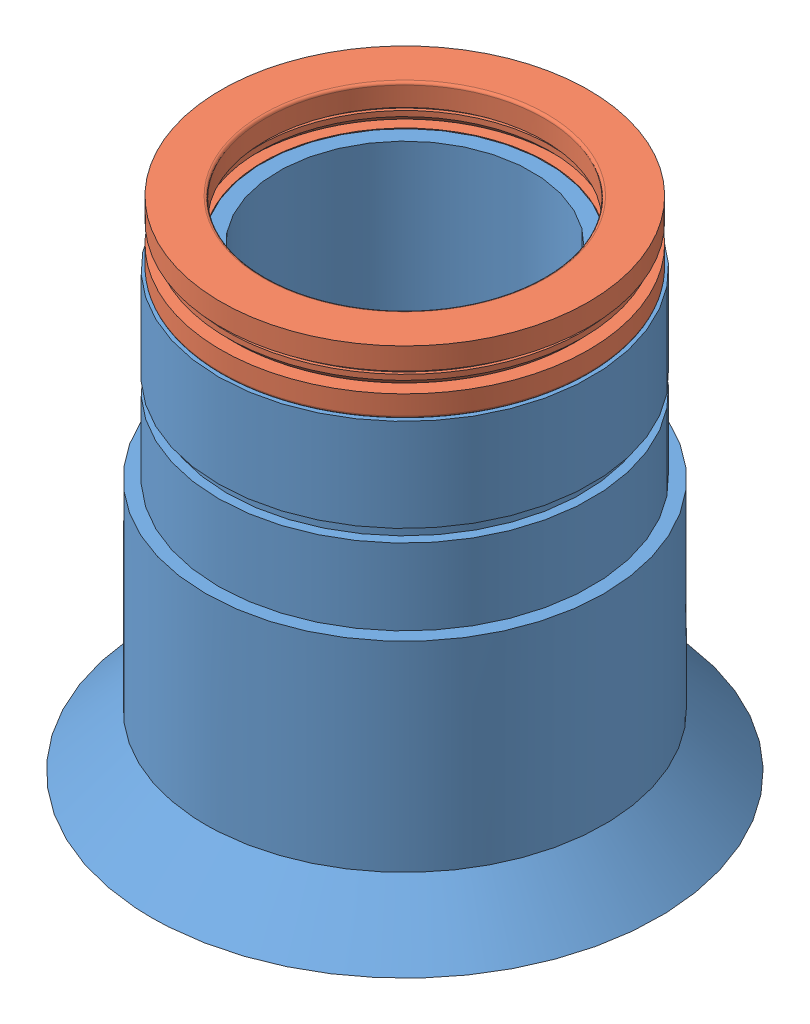
SolidWorks assembly 밑기둥과 베어링, configuration 기본. Lengths in mm.
Overall size (199.98 146.6 199.98).
2 component instances, 2 part files, 2 mates.
Components (placement in the parent):
- 밑기둥-1: 밑기둥 [기본] at origin size (199.98 130 199.98)
- single direction thrust ball bearing_ks-1: single direction thrust ball bearing_ks [KS B 2022 ST - 51122-S] at (0 170.8744 0) x (1 0 0) z (0 -1 0) size (145 145 25)
Mates (geometry in assembly coordinates):
- 동심2: concentric: circle of 밑기둥-1; circle of single direction thrust ball bearing_ks-1
- 일치1: coincident: plane of 밑기둥-1 through (0 158.3744 0) normal (0 1 0); plane of single direction thrust ball bearing_ks-1 through (0 158.3744 72.5) normal (0 -1 0)
